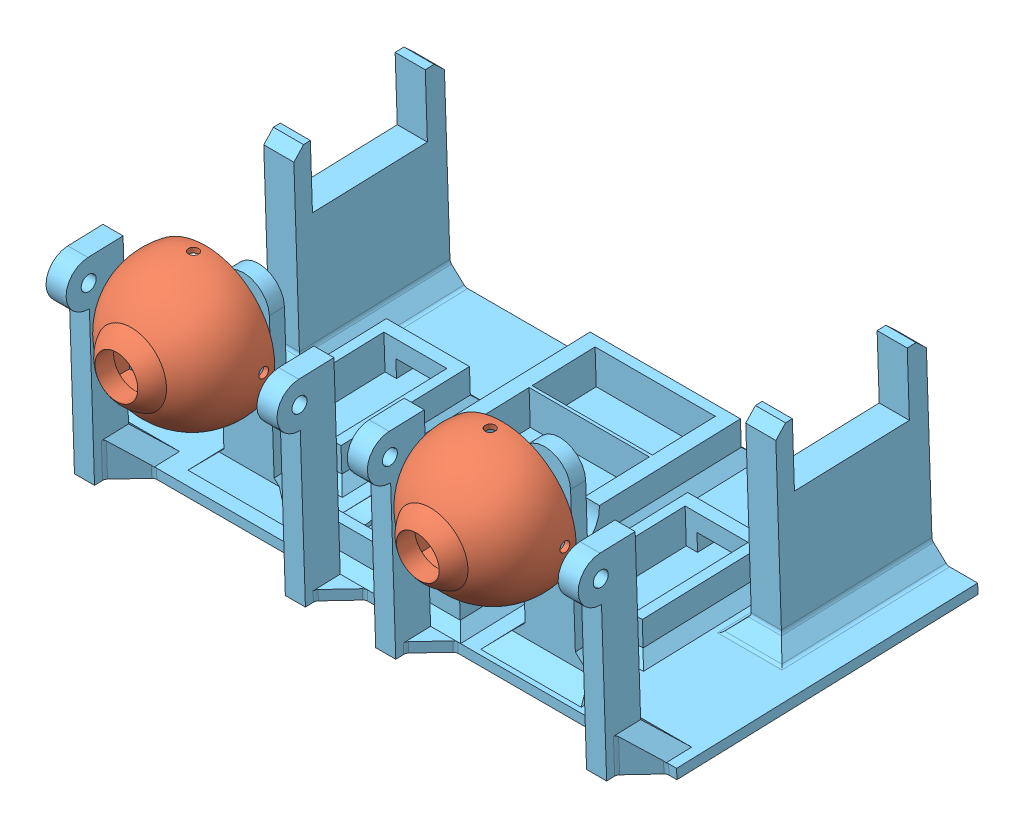
SolidWorks assembly EyeAssemblyFinal_StepppFile, configuration Default. Lengths in mm.
Overall size (120 49.81 82.5).
13 component instances, 5 part files, 10 mates.
Components (placement in the parent):
- UVHOLDERSLDPART-1: UVHOLDERSLDPART [Default] at (9.6546 9.8826 15.2328) size (20.5 15.75 3)
- eye ball-1: eye ball [Default] at (9.6546 9.8826 8.2328) x (0 0 -1) z (0 1 0) size (17.77 28 28)
- UVHOLDERSLDPART-2: UVHOLDERSLDPART [Default] at (69.6546 9.3742 15.216) x (1 0 0) z (0 -0.066023 0.997818) size (20.5 15.75 3)
- eye ball-2: eye ball [Default] at (69.6546 9.8364 8.2313) x (0 0.066023 -0.997818) z (0 -0.997818 -0.066023) size (17.77 28 28)
- UV_Final-1: UV_Final [Default] at (10.4248 15.8249 11.7172) x (-0.986642 -0.162816 -0.005381) z (0.162819 -0.986656 0) size (9.05 15.57 9.32)
  - UV cross spider[1].step-1: UV cross spider[1].step [Default] at (1.7499 4.175 5.7377) size (7.2 3 7.2)
  - UV Yoke[1].step-1: UV Yoke[1].step [Default] at (1.7499 11.8709 5.4867) x (1 0 0) z (0 -0.032589 -0.999469) size (9.01 10 9)
  - UV Yoke[1].step-2: UV Yoke[1].step [Default] at (1.7085 -3.5249 5.7377) x (0 0 -1) z (0.999986 -0.005381 0) size (9.01 10 9)
- UV_Final-2: UV_Final [Default] at (68.8845 3.6769 11.3157) x (0.986642 0.162816 0.005381) z (-0.162819 0.984503 0.065142) size (9.05 15.57 9.32)
  - UV cross spider[1].step-1: UV cross spider[1].step [Default] at (1.7499 4.175 5.7377) size (7.2 3 7.2)
  - UV Yoke[1].step-1: UV Yoke[1].step [Default] at (1.7499 11.8709 5.4867) x (1 0 0) z (0 -0.032589 -0.999469) size (9.01 10 9)
  - UV Yoke[1].step-2: UV Yoke[1].step [Default] at (1.7085 -3.5249 5.7377) x (0 0 -1) z (0.999986 -0.005381 0) size (9.01 10 9)
- BASE_v3_pasha-1: BASE_v3_pasha [Default] at (39.6546 -24.4519 -28.3208) x (-1 0 0) z (0 0.033029 -0.999454) size (120 40.7 71.5)
Mates (geometry in assembly coordinates):
- Coincident15: coincident anti-aligned: circle of UVHOLDERSLDPART-1; circle of UV_Final-1/UV Yoke[1].step-2
- Coincident17: coincident anti-aligned: circle of UVHOLDERSLDPART-2; circle of UV_Final-2/UV Yoke[1].step-2
- Coincident19: coincident anti-aligned: circle of UV_Final-1/UV Yoke[1].step-1; circle of BASE_v3_pasha-1
- Coincident20: coincident anti-aligned: circle of UV_Final-2/UV Yoke[1].step-1; circle of BASE_v3_pasha-1
- Parallel3: parallel aligned: line of UVHOLDERSLDPART-2 through (61.0052 3.8202 15.8507) axis (1 0 0); line of eye ball-2 through (64.6893 14.1975 16.5373) axis (1 0 0)
- Coincident22: coincident anti-aligned: plane of UVHOLDERSLDPART-2 through (69.6546 9.3082 16.2138) normal (0 -0.066023 0.997818); plane of eye ball-2 through (69.6546 9.3082 16.2138) normal (0 0.066023 -0.997818)
- Concentric4: concentric anti-aligned: circle of UVHOLDERSLDPART-2; circle of eye ball-2
- Parallel4: parallel anti-aligned: line of UVHOLDERSLDPART-1 through (1.0052 4.3826 15.2328) axis (1 0 0); line of eye ball-1 through (14.6199 4.9826 16.2328) axis (-1 0 0)
- Coincident24: coincident anti-aligned: plane of UVHOLDERSLDPART-1 through (9.6546 9.8826 16.2328) normal (0 0 1); plane of eye ball-1 through (9.6546 9.8826 16.2328) normal (0 0 -1)
- Concentric5: concentric anti-aligned: circle of UVHOLDERSLDPART-1; circle of eye ball-1
